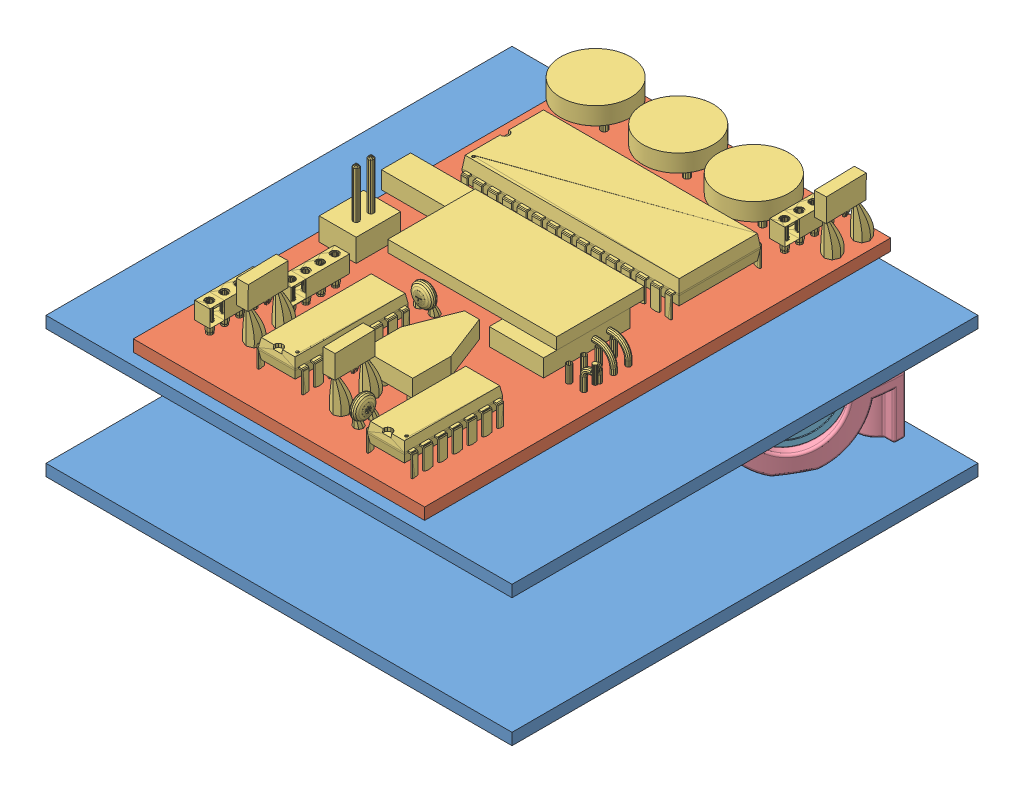
SolidWorks assembly Balise, configuration Défaut. Lengths in mm.
Overall size (80 40.5 82.66).
9 component instances, 5 part files, 19 mates.
Components (placement in the parent):
- plaque socle-2: plaque socle [Défaut] at (0 22 0) size (80 2 80)
- plaque Cicuit-1: plaque Cicuit [Défaut] at (65 28 0) x (-1 0 0) z (0 0 1) size (50 2 80)
- circuitE-1: circuitE [Défaut] at (40.0589 27.3249 -39.798) x (-1 0 0.000001) z (0 1 0) size (49.32 77.48 16.44)
- Support 180-1: Support 180 [Défaut] at (40 2 -77.6506) x (0 0 -1) z (1 0 0) size (30.36 10.63 60)
- Support 180-2: Support 180 [Défaut] at (40 22 -77.6506) x (0 0 -1) z (-1 0 0) size (30.36 10.63 60)
- Recepteur_Emetteur-1: Recepteur_Emetteur [Défaut] at (53.51 12 -69.8506) x (0.478251 0.291729 -0.828354) z (0.866025 0 0.5) size (16.3 16.3 20)
- Recepteur_Emetteur-2: Recepteur_Emetteur [Défaut] at (40 12 -62.0506) x (0.956501 0.291729 0) z (0 0 1) size (16.3 16.3 20)
- Recepteur_Emetteur-3: Recepteur_Emetteur [Défaut] at (26.49 12 -69.8506) x (0.478251 0.291729 0.828354) z (-0.866025 0 0.5) size (16.3 16.3 20)
- plaque socle-1: plaque socle [Défaut] at origin size (80 2 80)
Mates (geometry in assembly coordinates):
- Coïncidente12: coordinate: point of plaque socle-1; point of assembly
- Parallèle3: parallel aligned: plane of plaque Cicuit-1 through (65 28 0) normal (0 1 0); plane of circuitE-1 through (40.3596 29.7779 -56.6884) normal (0 1 0)
- Coïncidente5: coincident: plane of plaque Cicuit-1 through (65 28 0) normal (0 1 0); line of circuitE-1 through (55.8286 28 -48.9343) axis (0.000039 0 -1)
- Distance3: distance = 6.74 mm: plane of plaque Cicuit-1 through (15 26 0) normal (-1 0 0); line of circuitE-1 through (21.74 31.5471 -63.6746) axis (0 0 1)
- Distance4: distance = 6.2 mm: plane of plaque Cicuit-1 through (65 26 0) normal (0 0 1); line of circuitE-1 through (30.0588 24.8147 -6.2) axis (0 1 0)
- Coïncidente6: coincident anti-aligned: plane of Support 180-1 through (54 12 -77.6506) normal (0 1 0); plane of Support 180-2 through (26 12 -77.6506) normal (0 -1 0)
- Coaxiale1: concentric anti-aligned: cylinder of Support 180-1 through (52.5 2 -56) axis (0 1 0) radius 1.75; cylinder of Support 180-2 through (52.5 22 -56) axis (0 -1 0) radius 1.75
- Coïncidente7: coincident aligned: plane of Support 180-1 through (40 2 -77.6506) normal (0 0 -1); plane of Support 180-2 through (40 22 -77.6506) normal (0 0 -1)
- Coaxiale2: concentric aligned: cylinder of Support 180-1 through (40 12 -77.6506) axis (-0.866025 0 -0.5) radius 8.4; cylinder of Recepteur_Emetteur-1 through (63.9023 12 -63.8506) axis (-0.866025 0 -0.5) radius 8.15
- Coïncidente8: coincident anti-aligned: plane of Support 180-2 through (57.71 12 -77.1252) normal (0.866025 0 0.5); plane of Recepteur_Emetteur-1 through (53.51 12 -69.8506) normal (-0.866025 0 -0.5)
- Coïncidente10: coincident anti-aligned: plane of Support 180-1 through (54 2 -77.6506) normal (0 -1 0); plane of plaque socle-1 through (0 2 0) normal (0 1 0)
- Coïncidente13: coincident anti-aligned: plane of Support 180-2 through (26 22 -77.6506) normal (0 1 0); plane of plaque socle-2 through (0 22 0) normal (0 -1 0)
- Coaxiale8: concentric aligned: cylinder of Support 180-1 through (27.5 2 -56) axis (0 1 0) radius 1.75; cylinder of plaque socle-1 through (27.5 -0.001 -56) axis (0 1 0) radius 1.75
- Coaxiale9: concentric aligned: cylinder of Support 180-1 through (52.5 2 -56) axis (0 1 0) radius 1.75; cylinder of plaque socle-1 through (52.5 -0.001 -56) axis (0 1 0) radius 1.75
- Coaxiale10: concentric anti-aligned: cylinder of plaque socle-2 through (52.5 21.999 -56) axis (0 1 0) radius 1.75; cylinder of Support 180-2 through (52.5 22 -56) axis (0 -1 0) radius 1.75
- Coaxiale11: concentric anti-aligned: cylinder of plaque socle-2 through (27.5 21.999 -56) axis (0 1 0) radius 1.75; cylinder of Support 180-2 through (27.5 22 -56) axis (0 -1 0) radius 1.75
- Coaxiale12: concentric anti-aligned: cylinder of plaque socle-2 through (52.5 21.999 -56) axis (0 1 0) radius 1.75; cylinder of plaque Cicuit-1 through (52.5 28.001 -56) axis (0 -1 0) radius 1.75
- Coaxiale13: concentric anti-aligned: cylinder of plaque socle-2 through (27.5 21.999 -56) axis (0 1 0) radius 1.75; cylinder of plaque Cicuit-1 through (27.5 28.001 -56) axis (0 -1 0) radius 1.75
- Distance5: distance = 2 mm anti-aligned: plane of plaque Cicuit-1 through (65 26 0) normal (0 -1 0); plane of plaque socle-2 through (0 24 0) normal (0 1 0)
